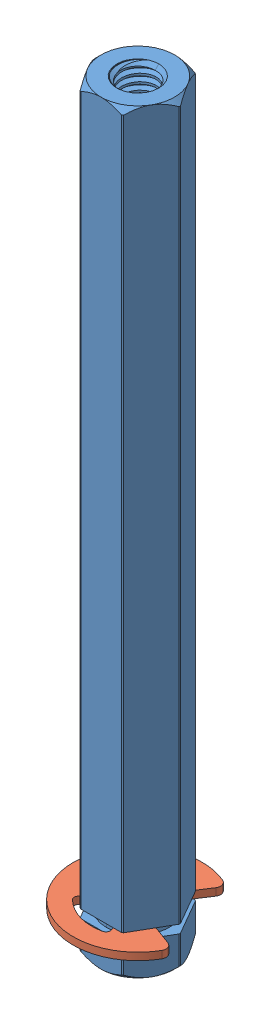
SolidWorks assembly 8mm x 72mm REX shaft with e-clip(2106-4008-0720), configuration Default. Lengths in mm.
Overall size (13.81 72.01 14.97).
3 component instances, 2 part files, 0 mates.
Components (placement in the parent):
- 2106-4008-0720 assembly.STEP-1: 2106-4008-0720 assembly.STEP [Default] at origin size (13.81 72.01 14.97)
  - 2106-4008-0720.STEP-1: 2106-4008-0720.STEP [Default] at (-43.354 23.419 6.9668) size (8 72.01 8.01)
  - 2106 Series 8mm REX e-clip.STEP-1: 2106 Series 8mm REX e-clip.STEP [Default] at (-43.354 27.069 6.9668) x (0 1 0) z (0.949119 0 -0.314917) size (0.7 12.3 10.47)
